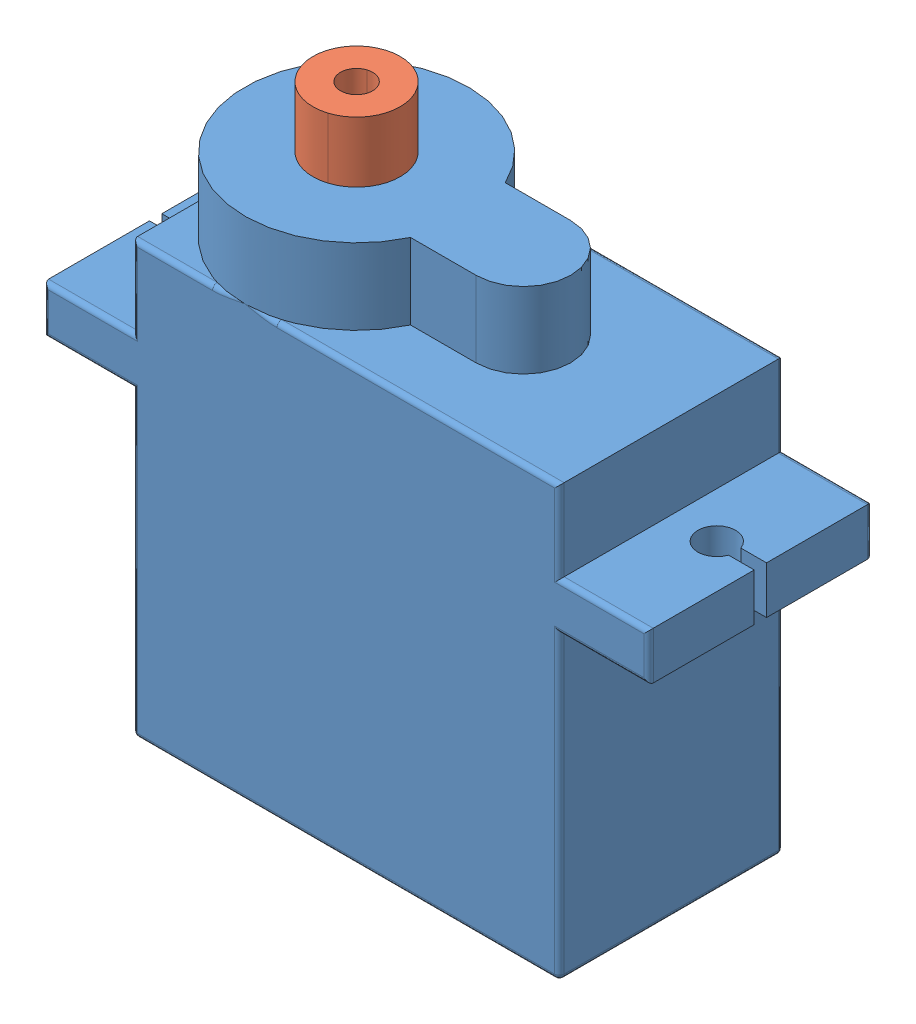
SolidWorks assembly sg90 micro servo, configuration Default. Lengths in mm.
Overall size (855.85 189.81 11.8).
2 component instances, 2 part files, 5 mates.
Components (placement in the parent):
- Part1-1: Part1 [Default] at (11.25 -26.7 0) size (855.85 189.81 11.8)
- axis.step-1: axis.step [Default] at (5.9 3.2 5.9) x (0.296886 0 0.954913) z (0 -1 0) size (4.6 4.6 7.2)
Mates (geometry in assembly coordinates):
- Concentric1: concentric anti-aligned: cylinder of Part1-1 through (5.9 0 5.9) axis (0 -1 0) radius 2.3; cylinder of axis.step-1 through (5.9 -4 5.9) axis (0 1 0) radius 2.3
- Coincident1: coincident anti-aligned: plane of Part1-1 through (22.5 -4 11.8) normal (0 1 0); plane of axis.step-1 through (5.9 -4 5.9) normal (0 -1 0)
- Coincident3: coincident anti-aligned: plane of Part1-1 through (11.25 -26.7 0) normal (0 0 -1)
- Coincident4: coincident aligned: plane of Part1-1 through (14.7 0 5.9) normal (0 1 0)
- Coincident5: coincident anti-aligned: plane of Part1-1 through (0 -26.7 11.8) normal (-1 0 0)
